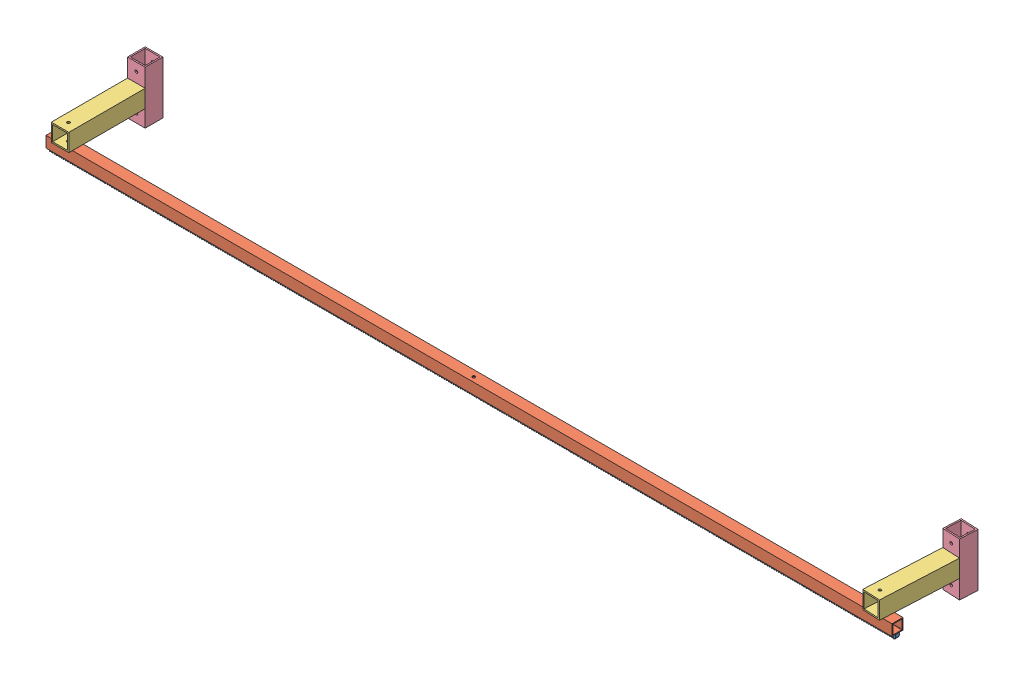
SolidWorks assembly Assem1, configuration Default. Lengths in mm.
Overall size (1219.2 78.67 136.94).
6 component instances, 4 part files, 14 mates.
Components (placement in the parent):
- 6295K232_MTL GEAR RACK--14-.5 DEG PRESSURE ANGLE-1: 6295K232_MTL GEAR RACK--14-.5 DEG PRESSURE ANGLE [6295K232] at (-7.7123 601.921 1203.3767) x (1 0 0) z (0 0 -1) size (1219.2 6.35 6.35)
- RackBacking1-1: RackBacking1 [Default] at (-617.3123 605.096 1211.3142) size (1219.2 15.88 15.88)
- straightBracket-1: straightBracket [Default] at (568.6685 620.971 1104.867) x (0.998767 0 0.049645) z (-0.049645 0 0.998767) size (25.4 25.4 110)
- straightBracket-2: straightBracket [Default] at (-604.6123 620.971 1106.4392) size (25.4 25.4 110)
- straightBracket2-1: straightBracket2 [Default] at (569.9295 670.2639 1079.4984) x (0.998767 0 0.049645) z (0 -1 0) size (25.4 25.4 76.2)
- straightBracket2-2: straightBracket2 [Default] at (-604.6123 672.7331 1081.0392) x (1 0 0) z (0 -1 0) size (25.4 25.4 76.2)
Mates (geometry in assembly coordinates):
- Coincident1: coincident anti-aligned: plane of 6295K232_MTL GEAR RACK--14-.5 DEG PRESSURE ANGLE-1 through (-617.3123 605.096 1200.2017) normal (0 1 0); plane of RackBacking1-1 through (601.8877 605.096 1173.2494) normal (0 -1 0)
- Coincident2: coincident aligned: plane of 6295K232_MTL GEAR RACK--14-.5 DEG PRESSURE ANGLE-1 through (601.8877 605.096 1200.2017) normal (1 0 0); plane of RackBacking1-1 through (601.8877 605.096 1173.2494) normal (1 0 0)
- Coincident3: coincident anti-aligned: plane of RackBacking1-1 through (601.8877 620.971 1173.2494) normal (0 1 0); plane of straightBracket-1 through (563.2076 620.971 1176.6666) normal (0 -1 0)
- Coincident4: coincident anti-aligned: circle of RackBacking1-1; cylinder of straightBracket-1 through (576.4877 646.371 1165.3119) axis (0 -1 0) radius 2
- Concentric1: concentric anti-aligned: cylinder of RackBacking1-1 through (-591.9123 605.096 1166.3744) axis (0 1 0) radius 2; cylinder of straightBracket-2 through (-591.9123 646.371 1166.3744) axis (0 -1 0) radius 2
- Coincident5: coincident anti-aligned: plane of RackBacking1-1 through (601.8877 620.971 1173.2494) normal (0 1 0); plane of straightBracket-2 through (-604.6123 620.971 1178.3744) normal (0 -1 0)
- Coincident6: coincident anti-aligned: plane of straightBracket-1 through (568.6685 620.971 1066.8022) normal (0.049645 0 -0.998767); plane of straightBracket2-1 through (568.6685 594.0639 1066.8022) normal (-0.049645 0 0.998767)
- Coincident7: coincident aligned: plane of straightBracket-1 through (588.5763 620.971 1177.9275) normal (0.998767 0 0.049645); plane of straightBracket2-1 through (595.2982 594.0639 1042.6945) normal (0.998767 0 0.049645)
- Coincident8: coincident anti-aligned: plane of straightBracket-2 through (-604.6123 620.971 1068.3744) normal (0 0 -1); plane of straightBracket2-2 through (-604.6123 596.5331 1068.3744) normal (0 0 1)
- Coincident9: coincident aligned: plane of straightBracket-2 through (-579.2123 620.971 1178.3744) normal (1 0 0); plane of straightBracket2-2 through (-579.2123 596.5331 1042.9744) normal (1 0 0)
- Parallel2: parallel aligned: plane of RackBacking1-1 through (601.8877 605.096 1173.2494) normal (0 0 1); plane of straightBracket-2 through (-604.6123 620.971 1178.3744) normal (0 0 1)
- Lock1: lock: unknown of straightBracket-2; unknown of straightBracket2-2
- Lock2: lock: unknown of straightBracket-1; unknown of straightBracket2-1
- Concentric2: concentric aligned: circle of 6295K232_MTL GEAR RACK--14-.5 DEG PRESSURE ANGLE-1; cylinder of RackBacking1-1 through (576.4877 605.096 1203.3767) axis (0 1 0) radius 2
